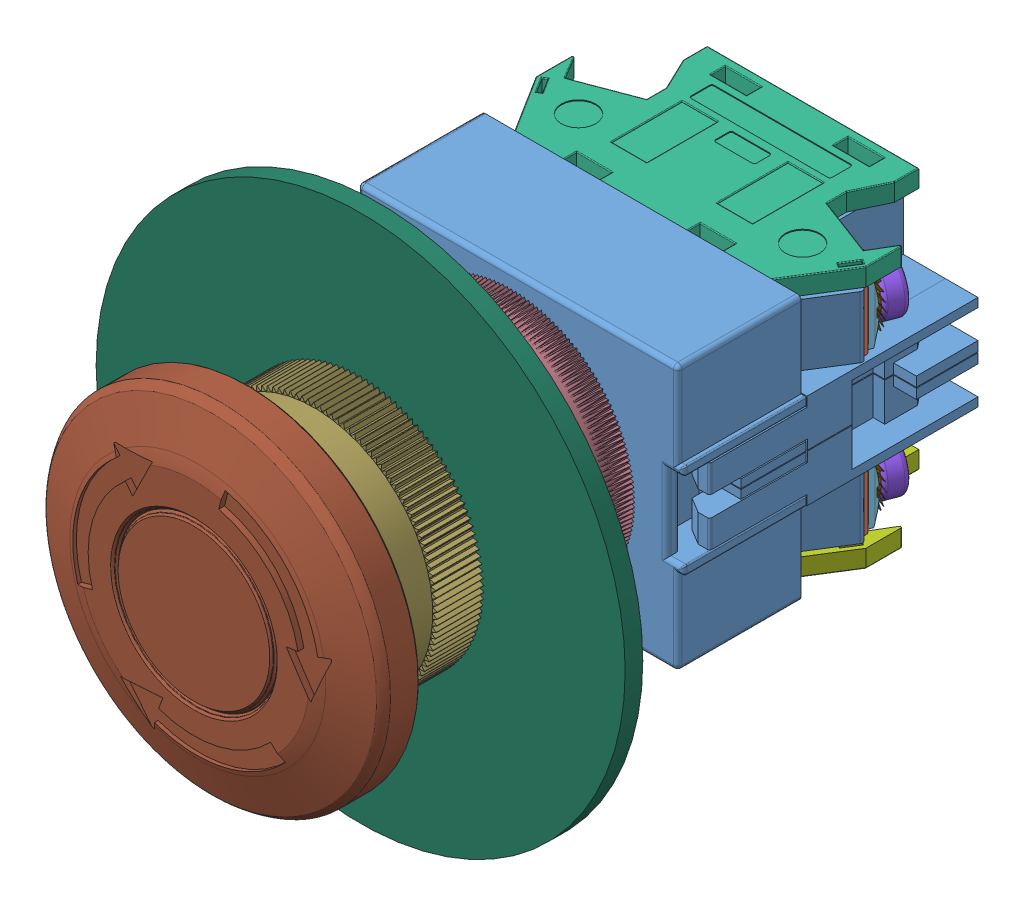
SolidWorks assembly EmergencyStopButton, configuration Valor predeterminado. Lengths in mm.
Overall size (60 60 70.49).
28 component instances, 15 part files, 3 mates.
Components (placement in the parent):
- corpo^EmergencyStopButton-1: corpo^EmergencyStopButton [Valor predeterminado] at origin size (37.4 30 52.27) (virtual)
- TERMINAL FIXO^EmergencyStopButton-1: TERMINAL FIXO^EmergencyStopButton [Valor predeterminado] at (-17.4785 5.4547 -5.6252) x (0 1 0) z (-0.936672 0 0.350207) size (6.7 2.25 8.2) (virtual)
- TERMINAL FIXO^EmergencyStopButton-2: TERMINAL FIXO^EmergencyStopButton [Valor predeterminado] at (17.4738 12.1798 -5.616) x (0 -1 0) z (0.93358 0 0.358368) size (6.7 2.25 8.2) (virtual)
- TERMINAL FIXO^EmergencyStopButton-4: TERMINAL FIXO^EmergencyStopButton [Valor predeterminado] at (17.473 -5.4807 -5.6271) x (0 -1 0) z (0.93358 0 0.358368) size (6.7 2.25 8.2) (virtual)
- TERMINAL FIXO^EmergencyStopButton-5: TERMINAL FIXO^EmergencyStopButton [Valor predeterminado] at (-17.462 -12.1795 -5.6261) x (0 1 0) z (-0.936672 0 0.350207) size (6.7 2.25 8.2) (virtual)
- MOLA2^EmergencyStopButton-1: MOLA2^EmergencyStopButton [Valor predeterminado] at (-0.0193 5.3596 -18.1661) size (2.5 2.89 10.2) (virtual)
- MOLA2^EmergencyStopButton-2: MOLA2^EmergencyStopButton [Valor predeterminado] at (-0.0225 -5.3272 -18.166) size (2.5 2.89 10.2) (virtual)
- MOLA^EmergencyStopButton-1: MOLA^EmergencyStopButton [Valor predeterminado] at (0.1318 0.0353 8.3646) x (1 0 0) z (0 -1 0) size (18.9 29.8 19.4) (virtual)
- washer^EmergencyStopButton-1: washer^EmergencyStopButton [Valor predeterminado] at (-14.3403 -8.8366 -8.8883) x (-0.350207 0 -0.936672) z (0.936672 0 -0.350207) size (1.12 6.65 6.8) (virtual)
- washer^EmergencyStopButton-2: washer^EmergencyStopButton [Valor predeterminado] at (14.4001 8.7838 -9.0181) x (0.350207 0 -0.936672) z (0.936672 0 0.350207) size (1.12 6.65 6.8) (virtual)
- washer^EmergencyStopButton-3: washer^EmergencyStopButton [Valor predeterminado] at (-14.3775 8.7959 -8.9721) x (-0.350207 0 -0.936672) z (0.936672 0 -0.350207) size (1.12 6.65 6.8) (virtual)
- washer^EmergencyStopButton-4: washer^EmergencyStopButton [Valor predeterminado] at (14.4115 -8.8453 -9.0338) x (0.350207 0 -0.936672) z (0.936672 0 0.350207) size (1.12 6.65 6.8) (virtual)
- COVER-VERDE^EmergencyStopButton-1: COVER-VERDE^EmergencyStopButton [Valor predeterminado] at (0.0015 -58.6356 0.0118) size (37.4 7 19.4) (virtual)
- COVER-VERMELHO^EmergencyStopButton-3: COVER-VERMELHO^EmergencyStopButton [Valor predeterminado] at (0.0018 58.4837 0.0125) x (-1 0 0) z (0 0 1) size (37.4 7 19.4) (virtual)
- screw^EmergencyStopButton-1: screw^EmergencyStopButton [Valor predeterminado] at (16.0259 8.7795 -12.9551) x (0.93358 0 0.358368) z (-0.358368 0 0.93358) size (5.54 5.54 7.5) (virtual)
- screw^EmergencyStopButton-2: screw^EmergencyStopButton [Valor predeterminado] at (-15.6991 8.7506 -13.0583) x (0.936672 0 -0.350207) z (0.350207 0 0.936672) size (5.54 5.54 7.5) (virtual)
- screw^EmergencyStopButton-3: screw^EmergencyStopButton [Valor predeterminado] at (-15.6791 -8.8081 -13.0535) x (0.939693 0 -0.34202) z (0.34202 0 0.939693) size (5.54 5.54 7.5) (virtual)
- screw^EmergencyStopButton-4: screw^EmergencyStopButton [Valor predeterminado] at (16.028 -8.8132 -12.9573) x (0.93358 0 0.358368) z (-0.358368 0 0.93358) size (5.54 5.54 7.5) (virtual)
- WASHER ESTRELADA^EmergencyStopButton-1: WASHER ESTRELADA^EmergencyStopButton [Valor predeterminado] at (15.1355 8.7808 -10.6344) x (0.936672 0 0.350207) z (-0.350207 0 0.936672) size (7.01 7.01 1.04) (virtual)
- WASHER ESTRELADA^EmergencyStopButton-2: WASHER ESTRELADA^EmergencyStopButton [Valor predeterminado] at (-14.8296 8.6127 -10.7013) x (0.93358 0 -0.358368) z (0.358368 0 0.93358) size (7.01 7.01 1.04) (virtual)
- WASHER ESTRELADA^EmergencyStopButton-3: WASHER ESTRELADA^EmergencyStopButton [Valor predeterminado] at (15.1184 -8.8527 -10.6478) x (0.936672 0 0.350207) z (-0.350207 0 0.936672) size (7.01 7.01 1.04) (virtual)
- WASHER ESTRELADA^EmergencyStopButton-4: WASHER ESTRELADA^EmergencyStopButton [Valor predeterminado] at (-14.9472 -8.9611 -10.6755) x (0.93358 0 -0.358368) z (0.358368 0 0.93358) size (7.01 7.01 1.04) (virtual)
- HASTE^EmergencyStopButton-1: HASTE^EmergencyStopButton [Valor predeterminado] at (0.0234 0.0366 3.7711) size (19.82 19.82 42) (virtual)
- CHAVE STOP^EmergencyStopButton-1: CHAVE STOP^EmergencyStopButton [Valor predeterminado] at (-0.0172 0.059 37.991) x (-0.48481 -0.87462 0) z (0 0 1) size (39.56 39.56 13) (virtual)
- PORCA-CROMO^EmergencyStopButton-1: PORCA-CROMO^EmergencyStopButton [Valor predeterminado] at (-0.025 0.0246 31.8152) size (27.98 27.99 14.01) (virtual)
- CONTRA-PORCA^EmergencyStopButton-1: CONTRA-PORCA^EmergencyStopButton [Valor predeterminado] at (0.0346 0.0248 14.7485) x (1 0 0) z (0 -1 0) size (28 8.41 28) (virtual)
- ANEL RETAINER^EmergencyStopButton-1: ANEL RETAINER^EmergencyStopButton [Valor predeterminado] at (-0.025 0.0044 21.9652) x (-1 0 0) z (0 0 1) size (27 27 2.45) (virtual)
- EmergencyStopSign^EmergencyStopButton-1: EmergencyStopSign^EmergencyStopButton [Default] at (0 0 29.8152) size (60 60 2) (virtual)
Mates (geometry in assembly coordinates):
- Distance2: distance = 7 mm anti-aligned: plane of Copy of PORCA-CROMO^EmergencyStopButton-1 through (-0.025 13.9887 31.8152) normal (0 0 -1); plane of ANEL RETAINER-1 through (-0.025 0.0044 24.8152) normal (0 0 1)
- Coincident1: coincident anti-aligned: plane of Copy of PORCA-CROMO^EmergencyStopButton-1 through (-0.025 13.9887 31.8152) normal (0 0 -1); plane of EmergencyStopSign^EmergencyStopButton-1 through (0 0 31.8152) normal (0 0 1)
- Concentric1: concentric aligned: cylinder of Copy of corpo1^EmergencyStopButton-1 through (0 0 22) axis (0 0 -1) radius 10.75; cylinder of EmergencyStopSign^EmergencyStopButton-1 through (0 0 31.8152) axis (0 0 -1) radius 11.25
